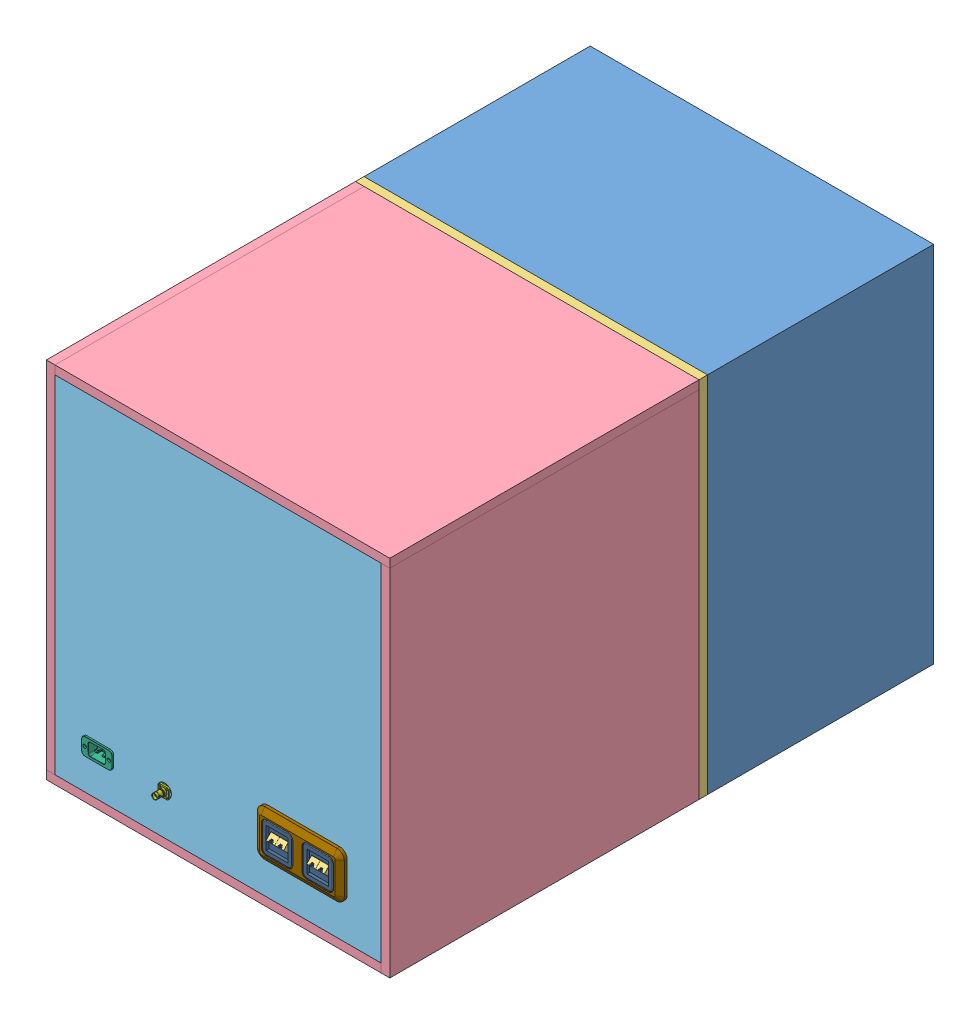
SolidWorks assembly Server, configuration Standard. Lengths in mm.
Overall size (600 687.5 968.25).
82 component instances, 25 part files, 27 mates.
Components (placement in the parent):
- Triton RBA-12-AD5-CAX-A1-1: Triton RBA-12-AD5-CAX-A1 [Standard] at (-276.3357 -337.3611 830.5) size (600 635 395)
- IPC 4U-4424-1: IPC 4U-4424 [Standard] at (240.1643 -104.0111 502.5) x (-1 0 0) z (0 0 -1) size (473 178 684)
- Verlängerung-1: Verlängerung [Standard] at (-43.1028 -81.9798 205) size (600 635 573.25)
  - Lochplatte-1: Lochplatte [Standard] at (-233.233 -255.3813 627.5) size (600 635 15)
  - Platten-1: Platten [Standard] at (-218.233 364.6187 1182.5) x (1 0 0) z (0 1 0) size (585 540 15)
  - Platten-2: Platten [Standard] at (-233.233 -255.3813 1182.5) x (1 0 0) z (0 1 0) size (585 540 15)
  - Platten-3: Platten [seite] at (-218.233 -240.3813 1182.5) x (0 1 0) z (-1 0 0) size (620 540 15)
  - Platten-4: Platten [seite] at (366.767 -255.3813 1182.5) x (0 1 0) z (-1 0 0) size (620 540 15)
  - Back-1: Back [Standard] at (-218.233 -240.3813 1167.5) size (570 605 15)
  - 17322-1: 17322 [Default] at (-142.233 -168.3813 1182.5) size (53 30 30)
  - 70551600-1: 70551600 [Default] at (-26.233 -168.3813 1200.75) x (0 0 -1) z (1 0 0) size (30 18.5 18.5)
  - Hohlwanddose-1: Hohlwanddose [Standard] at (180.767 -140.3813 1183.5) x (0 0 -1) z (1 0 0) size (60.7 71 71)
  - Hohlwanddose-2: Hohlwanddose [Standard] at (251.767 -140.3813 1183.5) x (0 0 -1) z (1 0 0) size (60.7 71 71)
  - Steckdose_2er-RJ45-1: Steckdose_2er-RJ45 [Standard] at (122.9666 -248.0462 1183.3552) size (152 80 25.23)
    - Wandplatte-1: Wandplatte [2er] at (17.3004 67.6649 10.1448) size (152 80 11)
    - Steckdose-RJ45-1: Steckdose-RJ45 [Standard] at (177.7047 18.6812 -53.8826) x (0 -1 0) z (0 0 1) size (54 54 25.23)
      - Buchse-RJ45-1: Buchse-RJ45 [Standard] at (-88.9836 -48.9043 64.0274) size (54 54 6.5)
      - 65864-1: 65864 [Default] at (-88.8386 -41.2043 53.1274) size (17.49 15.42 25.23)
        - 65864_01-1: 65864_01 [Default] at origin size (9.69 0.75 13.83)
        - 65864_02-1: 65864_02 [Default] at origin size (9.44 0.68 13.83)
        - 65864_03-1: 65864_03 [Default] at origin size (9.69 0.61 13.84)
        - 65864_04-1: 65864_04 [Default] at origin size (9.44 0.54 13.83)
        - 65864_05-1: 65864_05 [Default] at origin size (9.69 0.54 13.82)
        - 65864_06-1: 65864_06 [Default] at origin size (9.44 0.6 13.83)
        - 65864_07-1: 65864_07 [Default] at origin size (9.69 0.68 13.83)
        - 65864_08-1: 65864_08 [Default] at origin size (9.44 0.75 13.83)
        - 65864_09-1: 65864_09 [Default] at origin size (17.11 15.1 23.65)
        - 65864_10-1: 65864_10 [Default] at origin size (6.36 10.31 6.36)
        - 65864_11-1: 65864_11 [Default] at origin size (17.49 15.42 25.23)
      - 65864-2: 65864 [Default] at (-88.8386 -56.6043 53.1274) size (17.49 15.42 25.23)
        - 65864_01-1: 65864_01 [Default] at origin size (9.69 0.75 13.83)
        - 65864_02-1: 65864_02 [Default] at origin size (9.44 0.68 13.83)
        - 65864_03-1: 65864_03 [Default] at origin size (9.69 0.61 13.84)
        - 65864_04-1: 65864_04 [Default] at origin size (9.44 0.54 13.83)
        - 65864_05-1: 65864_05 [Default] at origin size (9.69 0.54 13.82)
        - 65864_06-1: 65864_06 [Default] at origin size (9.44 0.6 13.83)
        - 65864_07-1: 65864_07 [Default] at origin size (9.69 0.68 13.83)
        - 65864_08-1: 65864_08 [Default] at origin size (9.44 0.75 13.83)
        - 65864_09-1: 65864_09 [Default] at origin size (17.11 15.1 23.65)
        - 65864_10-1: 65864_10 [Default] at origin size (6.36 10.31 6.36)
        - 65864_11-1: 65864_11 [Default] at origin size (17.49 15.42 25.23)
    - Steckdose-RJ45-2: Steckdose-RJ45 [Standard] at (106.7047 18.6812 -53.8826) x (0 -1 0) z (0 0 1) size (54 54 25.23)
      - Buchse-RJ45-1: Buchse-RJ45 [Standard] at (-88.9836 -48.9043 64.0274) size (54 54 6.5)
      - 65864-1: 65864 [Default] at (-88.8386 -41.2043 53.1274) size (17.49 15.42 25.23)
        - 65864_01-1: 65864_01 [Default] at origin size (9.69 0.75 13.83)
        - 65864_02-1: 65864_02 [Default] at origin size (9.44 0.68 13.83)
        - 65864_03-1: 65864_03 [Default] at origin size (9.69 0.61 13.84)
        - 65864_04-1: 65864_04 [Default] at origin size (9.44 0.54 13.83)
        - 65864_05-1: 65864_05 [Default] at origin size (9.69 0.54 13.82)
        - 65864_06-1: 65864_06 [Default] at origin size (9.44 0.6 13.83)
        - 65864_07-1: 65864_07 [Default] at origin size (9.69 0.68 13.83)
        - 65864_08-1: 65864_08 [Default] at origin size (9.44 0.75 13.83)
        - 65864_09-1: 65864_09 [Default] at origin size (17.11 15.1 23.65)
        - 65864_10-1: 65864_10 [Default] at origin size (6.36 10.31 6.36)
        - 65864_11-1: 65864_11 [Default] at origin size (17.49 15.42 25.23)
      - 65864-2: 65864 [Default] at (-88.8386 -56.6043 53.1274) size (17.49 15.42 25.23)
        - 65864_01-1: 65864_01 [Default] at origin size (9.69 0.75 13.83)
        - 65864_02-1: 65864_02 [Default] at origin size (9.44 0.68 13.83)
        - 65864_03-1: 65864_03 [Default] at origin size (9.69 0.61 13.84)
        - 65864_04-1: 65864_04 [Default] at origin size (9.44 0.54 13.83)
        - 65864_05-1: 65864_05 [Default] at origin size (9.69 0.54 13.82)
        - 65864_06-1: 65864_06 [Default] at origin size (9.44 0.6 13.83)
        - 65864_07-1: 65864_07 [Default] at origin size (9.69 0.68 13.83)
        - 65864_08-1: 65864_08 [Default] at origin size (9.44 0.75 13.83)
        - 65864_09-1: 65864_09 [Default] at origin size (17.11 15.1 23.65)
        - 65864_10-1: 65864_10 [Default] at origin size (6.36 10.31 6.36)
        - 65864_11-1: 65864_11 [Default] at origin size (17.49 15.42 25.23)
- caster_2001_5-02-1: caster_2001_5-02 [Default] at (-203.8357 -370.8611 510) size (41 52.5 45)
  - caster_2001_5-02_01-1: caster_2001_5-02_01 [Default] at origin size (22 38 38)
  - caster_2001_5-02_02-1: caster_2001_5-02_02 [Default] at origin size (41 38.4 45)
- caster_2001_5-02-2: caster_2001_5-02 [Default] at (251.1643 -370.8611 1315) size (41 52.5 45)
  - caster_2001_5-02_01-1: caster_2001_5-02_01 [Default] at origin size (22 38 38)
  - caster_2001_5-02_02-1: caster_2001_5-02_02 [Default] at origin size (41 38.4 45)
- caster_2001_5-02-3: caster_2001_5-02 [Default] at (251.1643 -370.8611 510) size (41 52.5 45)
  - caster_2001_5-02_01-1: caster_2001_5-02_01 [Default] at origin size (22 38 38)
  - caster_2001_5-02_02-1: caster_2001_5-02_02 [Default] at origin size (41 38.4 45)
- caster_2001_5-02-4: caster_2001_5-02 [Default] at (-203.8357 -370.8611 1315) size (41 52.5 45)
  - caster_2001_5-02_01-1: caster_2001_5-02_01 [Default] at origin size (22 38 38)
  - caster_2001_5-02_02-1: caster_2001_5-02_02 [Default] at origin size (41 38.4 45)
- USV-1: USV [Standard] at (240.1643 -192.8611 502.5) x (-1 0 0) z (0 0 -1) size (473 89 509)
- 3com-eth-sfp-switch-1: 3com-eth-sfp-switch [Default] at (23.868 -236.86 587.209) x (-1 -0.000472 0) z (0 0 -1) size (470.41 43.94 178.3)
- 3com-eth-sfp-switch-2: 3com-eth-sfp-switch [Default] at (23.868 -281.31 587.209) x (-1 -0.000472 0) z (0 0 -1) size (470.41 43.94 178.3)
Mates (geometry in assembly coordinates):
- Deckungsgleich5: coincident anti-aligned: plane of Triton RBA-12-AD5-CAX-A1-1 through (-276.3357 -337.3611 832.5) normal (0 0 1); plane of Verlängerung-1/Lochplatte-1 through (-276.3357 -337.3611 832.5) normal (0 0 -1)
- Deckungsgleich6: coincident anti-aligned: circle of Triton RBA-12-AD5-CAX-A1-1; cylinder of Verlängerung-1/Lochplatte-1 through (-185.3357 276.6389 847.5) axis (0 0 -1) radius 6
- Konzentrisch1: concentric anti-aligned: cylinder of Triton RBA-12-AD5-CAX-A1-1 through (232.6643 -316.3611 830.5) axis (0 0 1) radius 6; cylinder of Verlängerung-1/Lochplatte-1 through (232.6643 -316.3611 847.5) axis (0 0 -1) radius 6
- Deckungsgleich7: coincident anti-aligned: plane of Verlängerung-1/Platten-2 through (-276.3357 -337.3611 1387.5) normal (0 -1 0); plane of caster_2001_5-02-1/caster_2001_5-02_02-1 through (-218.3357 -337.3611 517.5147) normal (0 1 0)
- Deckungsgleich8: coincident anti-aligned: plane of Verlängerung-1/Platten-2 through (-276.3357 -337.3611 1387.5) normal (0 -1 0); plane of caster_2001_5-02-2/caster_2001_5-02_02-1 through (236.6643 -337.3611 1322.5147) normal (0 1 0)
- Deckungsgleich9: coincident anti-aligned: plane of Triton RBA-12-AD5-CAX-A1-1 through (-276.3357 -337.3611 832.5) normal (0 -1 0); plane of caster_2001_5-02-3/caster_2001_5-02_02-1 through (236.6643 -337.3611 517.5147) normal (0 1 0)
- Deckungsgleich10: coincident anti-aligned: plane of Triton RBA-12-AD5-CAX-A1-1 through (-276.3357 -337.3611 832.5) normal (0 -1 0); plane of caster_2001_5-02-4/caster_2001_5-02_02-1 through (-218.3357 -337.3611 1322.5147) normal (0 1 0)
- Deckungsgleich11: coincident aligned: plane of caster_2001_5-02-1/caster_2001_5-02_02-1 through (-216.3357 -337.3611 517.5147) normal (-1 0 0); plane of caster_2001_5-02-4/caster_2001_5-02_02-1 through (-216.3357 -337.3611 1322.5147) normal (-1 0 0)
- Deckungsgleich12: coincident aligned: plane of caster_2001_5-02-2/caster_2001_5-02_02-1 through (237.1643 -337.3611 1337.5) normal (0 0 1); plane of caster_2001_5-02-4/caster_2001_5-02_02-1 through (-217.8357 -337.3611 1337.5) normal (0 0 1)
- Deckungsgleich13: coincident aligned: plane of caster_2001_5-02-2/caster_2001_5-02_02-1 through (263.6643 -337.3611 1322.5147) normal (1 0 0); plane of caster_2001_5-02-3/caster_2001_5-02_02-1 through (263.6643 -337.3611 517.5147) normal (1 0 0)
- Deckungsgleich14: coincident aligned: plane of caster_2001_5-02-1/caster_2001_5-02_02-1 through (-217.8357 -337.3611 487.5) normal (0 0 -1); plane of caster_2001_5-02-3/caster_2001_5-02_02-1 through (237.1643 -337.3611 487.5) normal (0 0 -1)
- Abstand2: distance = 50 mm aligned: plane of caster_2001_5-02-1/caster_2001_5-02_02-1 through (-217.8357 -337.3611 487.5) normal (0 0 -1); plane of Triton RBA-12-AD5-CAX-A1-1 through (-276.3357 -337.3611 437.5) normal (0 0 -1)
- Abstand3: distance = 60 mm aligned: plane of caster_2001_5-02-1/caster_2001_5-02_02-1 through (-216.3357 -337.3611 517.5147) normal (-1 0 0); plane of Triton RBA-12-AD5-CAX-A1-1 through (-276.3357 -337.3611 832.5) normal (-1 0 0)
- Abstand4: distance = 60 mm aligned: plane of caster_2001_5-02-3/caster_2001_5-02_02-1 through (263.6643 -337.3611 517.5147) normal (1 0 0); plane of Triton RBA-12-AD5-CAX-A1-1 through (323.6643 -337.3611 832.5) normal (1 0 0)
- Abstand5: distance = 50 mm aligned: plane of caster_2001_5-02-2/caster_2001_5-02_02-1 through (237.1643 -337.3611 1337.5) normal (0 0 1); plane of Verlängerung-1/Platten-2 through (-276.3357 -322.3611 1387.5) normal (0 0 1)
- Deckungsgleich19: coincident anti-aligned: plane of Triton RBA-12-AD5-CAX-A1-1 through (-192.8357 275.6389 506.5) normal (1 0 0); plane of IPC 4U-4424-1 through (-192.8357 73.9889 502.5) normal (-1 0 0)
- Deckungsgleich20: coincident anti-aligned: plane of Triton RBA-12-AD5-CAX-A1-1 through (-276.3357 -337.3611 502.5) normal (0 0 -1); plane of IPC 4U-4424-1 through (240.1643 -104.0111 502.5) normal (0 0 1)
- Konzentrisch2: concentric anti-aligned: cylinder of Triton RBA-12-AD5-CAX-A1-1 through (-202.8357 -97.5611 496.5) axis (0 0 1) radius 2.5; cylinder of IPC 4U-4424-1 through (-202.8357 -97.5611 508.5) axis (0 0 -1) radius 2.5
- Deckungsgleich21: coincident anti-aligned: plane of Triton RBA-12-AD5-CAX-A1-1 through (-276.3357 -337.3611 502.5) normal (0 0 -1); plane of USV-1 through (240.1643 -192.8611 502.5) normal (0 0 1)
- Deckungsgleich22: coincident anti-aligned: plane of Triton RBA-12-AD5-CAX-A1-1 through (240.1643 275.6389 506.5) normal (-1 0 0); plane of USV-1 through (240.1643 -103.8611 502.5) normal (1 0 0)
- Konzentrisch3: concentric anti-aligned: cylinder of Triton RBA-12-AD5-CAX-A1-1 through (250.1643 -186.4611 496.5) axis (0 0 1) radius 2.5; cylinder of USV-1 through (250.1643 -186.4611 508.5) axis (0 0 -1) radius 2.5
- Deckungsgleich23: coincident: plane of Triton RBA-12-AD5-CAX-A1-1 through (-276.3357 -337.3611 502.5) normal (0 0 -1); plane of 3com-eth-sfp-switch-1 through (258.8263 -192.5035 502.5) normal (0 0 1)
- Konzentrisch4: concentric: cylinder of Triton RBA-12-AD5-CAX-A1-1 through (250.1643 -199.1611 496.5) axis (0 0 1) radius 2.5; cylinder of 3com-eth-sfp-switch-1 through (250.1643 -199.1611 512.7233) axis (0 0 -1) radius 2.286
- Tangential1: tangent anti-aligned: cylinder of Triton RBA-12-AD5-CAX-A1-1 through (-202.8357 -199.1611 496.5) axis (0 0 1) radius 2.5; plane of 3com-eth-sfp-switch-1 through (-202.4626 -201.6609 512.7233) normal (-0.000472 1 0)
- Deckungsgleich26: coincident: plane of Triton RBA-12-AD5-CAX-A1-1 through (-276.3357 -337.3611 502.5) normal (0 0 -1); plane of 3com-eth-sfp-switch-2 through (259.0513 -237.2569 502.5) normal (0 0 1)
- Konzentrisch6: concentric: cylinder of Triton RBA-12-AD5-CAX-A1-1 through (250.1643 -243.6111 496.5) axis (0 0 1) radius 2.5; cylinder of 3com-eth-sfp-switch-2 through (250.1643 -243.6111 512.7233) axis (0 0 -1) radius 2.286
- Tangential2: tangent anti-aligned: cylinder of Triton RBA-12-AD5-CAX-A1-1 through (-202.8357 -243.6111 496.5) axis (0 0 1) radius 2.5; plane of 3com-eth-sfp-switch-2 through (-202.4626 -246.1109 512.7233) normal (-0.000472 1 0)
